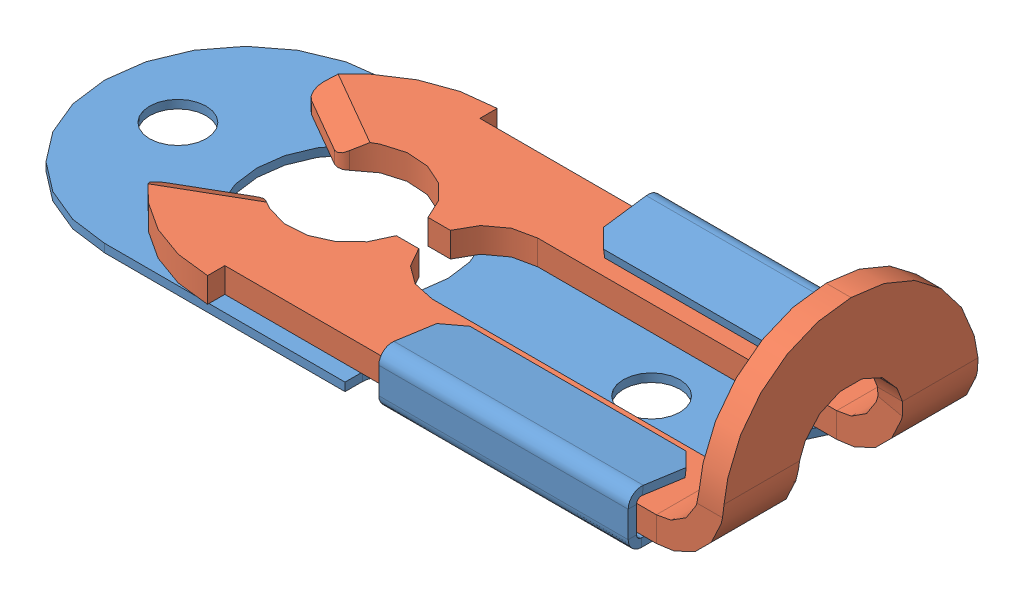
SolidWorks assembly Southco-TL-05-100-07, configuration Default. Lengths in mm.
Overall size (44.91 11.63 17.42).
2 component instances, 2 part files, 0 mates.
Components (placement in the parent):
- Southco-TL-05-100-07_150001-1: Southco-TL-05-100-07_150001 [Default] at origin size (40 3.19 17)
- Southco-TL-05-100-07_150002-1: Southco-TL-05-100-07_150002 [Default] at (0 0.627 0.001) x (0 0 1) z (-1 0 0) size (17.42 11 37.09)
